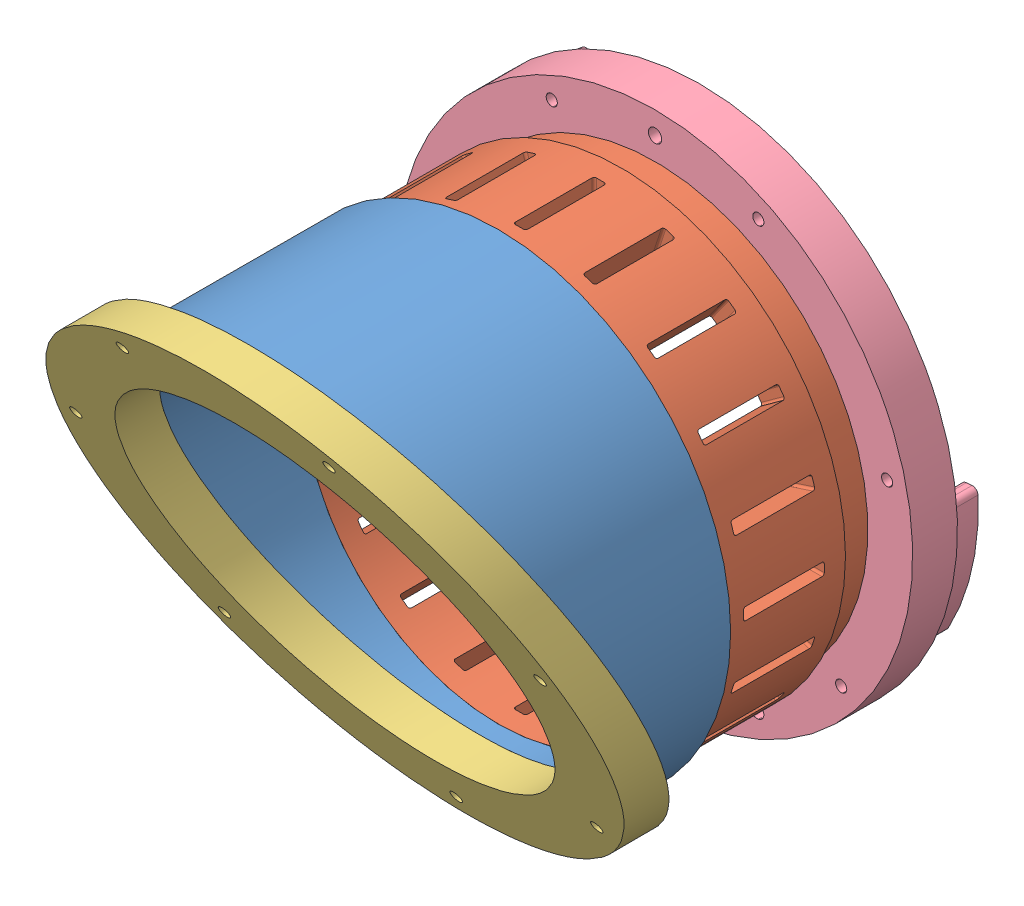
SolidWorks assembly L.Z.G V2.0, configuration Défaut. Lengths in mm.
Overall size (61.4 61.4 46.89).
4 component instances, 4 part files, 15 mates.
Components (placement in the parent):
- Lentille - Tube - C Attaque-1: Lentille - Tube - C Attaque [Défaut] at (-23.9577 -14.0223 42.673) x (-1 0 0) z (0 0 1) size (41.5 41.5 21.15)
- Lentille - Tube Attaque-1: Lentille - Tube Attaque [Défaut] at (-23.9577 -14.0223 60.673) x (-1 0 0) z (0 0 -1) size (40 40 14)
- Lentille - Rondelle N°1 Attaque-2: Lentille - Rondelle N°1 Attaque [Défaut] at (-23.9577 -14.0223 81.5266) x (1 0 0) z (0 0 -1) size (46 46 27.44)
- Lentille - Rondelle N°2 V3 2GAUCHE-1: Lentille - Rondelle N°2 V3 2GAUCHE [Défaut] at (-23.9577 -14.0223 24.673) x (0.900969 0.433884 0) z (0 0 1) size (46 46 6.6)
Mates (geometry in assembly coordinates):
- Coïncidente1: coincident: plane of ? through (-28.7484 25.144 55.7191) normal (0 0.45399 -0.891007); plane of ? through (15.0016 -18.606 33.4273) normal (0 -0.45399 0.891007)
- Coaxiale1: concentric: cylinder of ? through (-5.7484 2.144 59.7191) axis (0 0 -1) radius 17.5; cylinder of ? through (-5.7484 2.144 80.4273) axis (0 0 -1) radius 17.5
- Parallèle1: parallel: plane of assembly through (0 0 0) normal (0 0 1); plane of Lentille - Tube - C Attaque-1 through (-23.9577 -14.0223 42.673) normal (0 0 -1); plane of assembly
- Parallèle2: parallel: plane of ? through (-5.7484 2.144 19.7191) normal (1 0 0); plane of assembly through (0 0 0) normal (1 0 0)
- Coïncidente2: coincident: plane of assembly; plane of assembly; plane of Lentille - Tube - C Attaque-1 through (-23.9577 -14.0223 42.673) normal (0 0 -1); plane of Lentille - Tube Attaque-1 through (-23.9577 -34.0223 42.673) normal (0 0 1)
- Coaxiale2: concentric: cylinder of assembly; cylinder of assembly; cylinder of Lentille - Tube - C Attaque-1 through (-23.9577 -14.0223 89.673) axis (0 0 -1) radius 17.5; cylinder of Lentille - Tube Attaque-1 through (-23.9577 -14.0223 23.673) axis (0 0 1) radius 17.5
- Coïncidente3: coincident: line of ?; line of ? through (-5.7484 22.144 31.5361) axis (0 0 -1)
- Coïncidente4: coincident: plane of ? through (-6.3772 -2.6108 20.1949) normal (0 0 -1); plane of ? through (-6.3772 -2.6108 20.1949) normal (0 0 1)
- Coaxiale3: concentric: cylinder of ? through (-6.3772 -2.6108 15.1949) axis (0 0 1) radius 17.5; cylinder of ? through (-6.3772 -2.6108 20.1949) axis (0 0 -1) radius 17.5
- Coïncidente5: coincident: plane of assembly; plane of assembly; plane of Lentille - Tube - C Attaque-1 through (-3.2077 -34.7723 42.673) normal (0 -0.45399 0.891007); plane of Lentille - Rondelle N°1 Attaque-2 through (-46.9577 8.9777 64.9647) normal (0 0.45399 -0.891007)
- Coaxiale4: concentric: cylinder of assembly; cylinder of assembly; cylinder of Lentille - Tube - C Attaque-1 through (-23.9577 -14.0223 89.673) axis (0 0 -1) radius 17.5; cylinder of Lentille - Rondelle N°1 Attaque-2 through (-23.9577 -14.0223 41.5266) axis (0 0 1) radius 17.5
- Coaxiale5: concentric: cylinder of ? through (-6.3772 -23.8608 20.1949) axis (0 0 -1) radius 0.5; cylinder of ? through (-6.3772 -23.8608 33.0485) axis (0 0 1) radius 0.5
- Coaxiale6: concentric: cylinder of assembly; cylinder of assembly; cylinder of Lentille - Tube Attaque-1 through (-23.9577 -14.0223 23.673) axis (0 0 1) radius 17.5; cylinder of Lentille - Rondelle N°2 V3 2GAUCHE-1 through (-23.9577 -14.0223 28.673) axis (0 0 -1) radius 17.5
- Coïncidente6: coincident: plane of assembly; plane of assembly; plane of Lentille - Tube Attaque-1 through (-23.9577 -14.0223 28.673) normal (0 0 -1); plane of Lentille - Rondelle N°2 V3 2GAUCHE-1 through (-23.9577 -14.0223 28.673) normal (0 0 1)
- Coaxiale7: concentric: cylinder of assembly; cylinder of assembly; cylinder of Lentille - Rondelle N°1 Attaque-2 through (-23.9577 -35.2723 41.5266) axis (0 0 1) radius 0.5; cylinder of Lentille - Rondelle N°2 V3 2GAUCHE-1 through (-23.9577 -35.2723 28.673) axis (0 0 -1) radius 0.5
